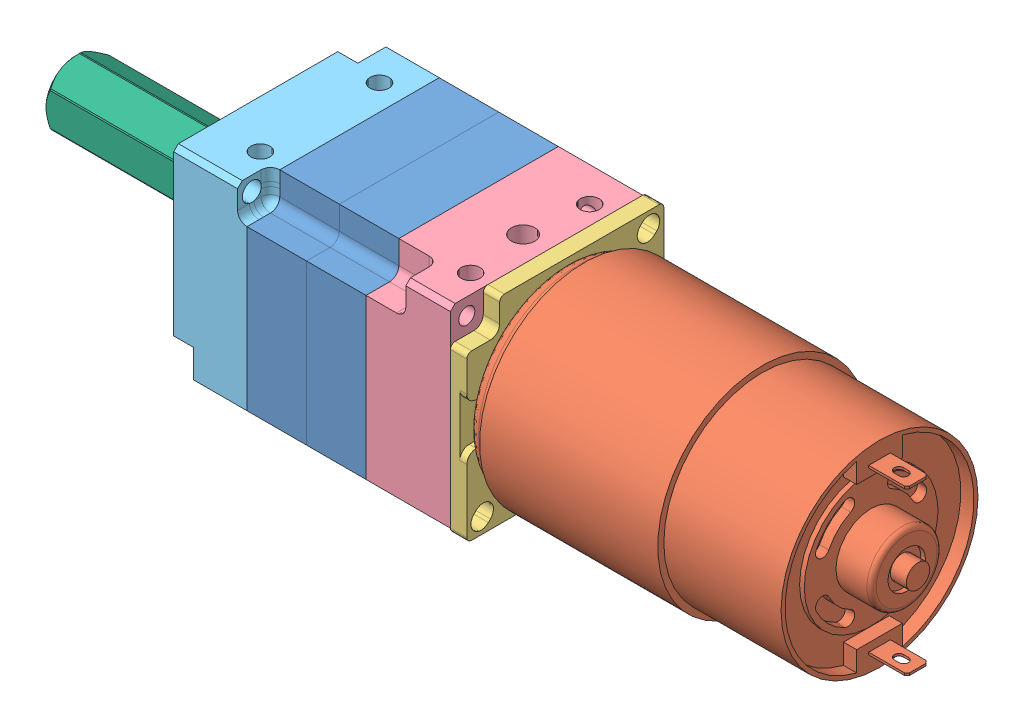
SolidWorks assembly VEXPro VersaPlanetary 2 Stage with 775pro, configuration Default. Lengths in mm.
Overall size (261.57 245.63 1161.31).
7 component instances, 6 part files, 16 mates.
Components (placement in the parent):
- VersaPlanetary Ring Gear Add-on Kit-1: VersaPlanetary Ring Gear Add-on Kit [Default] at (-176.7243 202.3342 1100.186) x (0 0 1) z (1 0 0) size (42 42 14.5)
- VersaPlanetary Ring Gear Add-on Kit-2: VersaPlanetary Ring Gear Add-on Kit [Default] at (-164.0243 202.3342 1100.186) x (0 0 1) z (1 0 0) size (42 42 14.5)
- 775Pro-1: 775Pro [Default] at (-136.1743 202.3342 1100.186) size (88 44.6 44.6)
- RS-775 Mounting Plate-1: RS-775 Mounting Plate [Default] at (-137.9243 202.3342 1100.186) x (0 0 -1) z (1 0 0) size (42 42 5.3)
- VersaPlanetary Input Housing-1: VersaPlanetary Input Housing [Default] at (-147.1743 202.3342 1100.186) x (0 -1 0) z (1 0 0) size (42 42 18)
- VersaPlanetary Output Housing-1: VersaPlanetary Output Housing [Default] at (-159.8743 202.3342 1100.186) x (0 1 0) z (1 0 0) size (42 42 17.13)
- VersaPlanetary .500 Hex Output-1: VersaPlanetary .500 Hex Output [Default] at (-190.8221 202.3342 1100.186) x (0 0 1) z (-1 0 0) size (17 17 64.13)
Mates (geometry in assembly coordinates):
- Concentric1: concentric aligned: cylinder of VersaPlanetary Ring Gear Add-on Kit-1 through (-177.3743 202.3342 1100.186) axis (1 0 0) radius 20.025; cylinder of VersaPlanetary Ring Gear Add-on Kit-2 through (-169.9243 202.3342 1100.186) axis (1 0 0) radius 20
- Coincident1: coincident anti-aligned: plane of VersaPlanetary Ring Gear Add-on Kit-1 through (-170.3743 181.3342 1121.186) normal (1 0 0); plane of VersaPlanetary Ring Gear Add-on Kit-2 through (-170.3743 181.3342 1121.186) normal (-1 0 0)
- Concentric4: concentric aligned: cylinder of 775Pro-1 through (-141.1743 202.3342 1100.186) axis (1 0 0) radius 8.65; cylinder of RS-775 Mounting Plate-1 through (-136.1743 202.3342 1100.186) axis (1 0 0) radius 8.65
- Coincident3: coincident anti-aligned: plane of 775Pro-1 through (-136.1743 202.3342 1100.186) normal (-1 0 0); plane of RS-775 Mounting Plate-1 through (-136.1743 202.3342 1100.186) normal (1 0 0)
- Coincident4: coincident anti-aligned: plane of VersaPlanetary Ring Gear Add-on Kit-2 through (-157.6743 181.3342 1121.186) normal (1 0 0); plane of VersaPlanetary Input Housing-1 through (-157.6743 186.3342 1084.186) normal (-1 0 0)
- Coincident5: coincident aligned: plane of VersaPlanetary Ring Gear Add-on Kit-2 through (-157.6743 223.3342 1079.186) normal (0 0 -1); plane of VersaPlanetary Input Housing-1 through (-139.6743 222.3342 1079.186) normal (0 0 -1)
- Coincident6: coincident aligned: plane of VersaPlanetary Ring Gear Add-on Kit-1 through (-170.3743 223.3342 1079.186) normal (0 0 -1); plane of VersaPlanetary Ring Gear Add-on Kit-2 through (-157.6743 223.3342 1079.186) normal (0 0 -1)
- Concentric5: concentric aligned: cylinder of VersaPlanetary Ring Gear Add-on Kit-2 through (-164.6743 202.3342 1100.186) axis (1 0 0) radius 20.025; cylinder of VersaPlanetary Input Housing-1 through (-157.6743 202.3342 1100.186) axis (1 0 0) radius 20.025
- Coincident7: coincident anti-aligned: plane of RS-775 Mounting Plate-1 through (-139.6743 202.3342 1100.186) normal (-1 0 0); plane of VersaPlanetary Input Housing-1 through (-139.6743 202.3342 1100.186) normal (1 0 0)
- Coincident8: coincident aligned: plane of RS-775 Mounting Plate-1 through (-139.6743 181.3342 1079.186) normal (0 0 -1); plane of VersaPlanetary Input Housing-1 through (-139.6743 222.3342 1079.186) normal (0 0 -1)
- Coincident9: coincident aligned: plane of RS-775 Mounting Plate-1 through (-139.6743 181.3342 1121.186) normal (0 -1 0); plane of VersaPlanetary Input Housing-1 through (-139.6743 181.3342 1080.186) normal (0 -1 0)
- Coincident10: coincident: plane of VersaPlanetary Ring Gear Add-on Kit-1 through (-183.0743 181.3342 1121.186) normal (-1 0 0); plane of VersaPlanetary Output Housing-1 through (-183.0743 212.8342 1100.186) normal (1 0 0)
- Coincident13: coincident: plane of VersaPlanetary Ring Gear Add-on Kit-1 through (-170.3743 223.3342 1121.186) normal (0 0 1); plane of VersaPlanetary Output Housing-1 through (-198.6993 223.3342 1121.186) normal (0 0 1)
- Coincident14: coincident aligned: plane of VersaPlanetary Ring Gear Add-on Kit-1 through (-170.3743 223.3342 1079.186) normal (0 1 0); plane of VersaPlanetary Output Housing-1 through (-198.6993 223.3342 1079.186) normal (0 1 0)
- Concentric6: concentric: cylinder of VersaPlanetary Output Housing-1 through (-198.5745 202.3342 1100.186) axis (-1 0 0) radius 7.5; cylinder of VersaPlanetary .500 Hex Output-1 through (-200.5745 202.3342 1100.186) axis (1 0 0) radius 7.4955
- Coincident15: coincident anti-aligned: plane of VersaPlanetary Output Housing-1 through (-198.5745 202.9656 1108.9132) normal (-1 0 0); plane of VersaPlanetary .500 Hex Output-1 through (-198.5745 202.3342 1100.186) normal (1 0 0)
